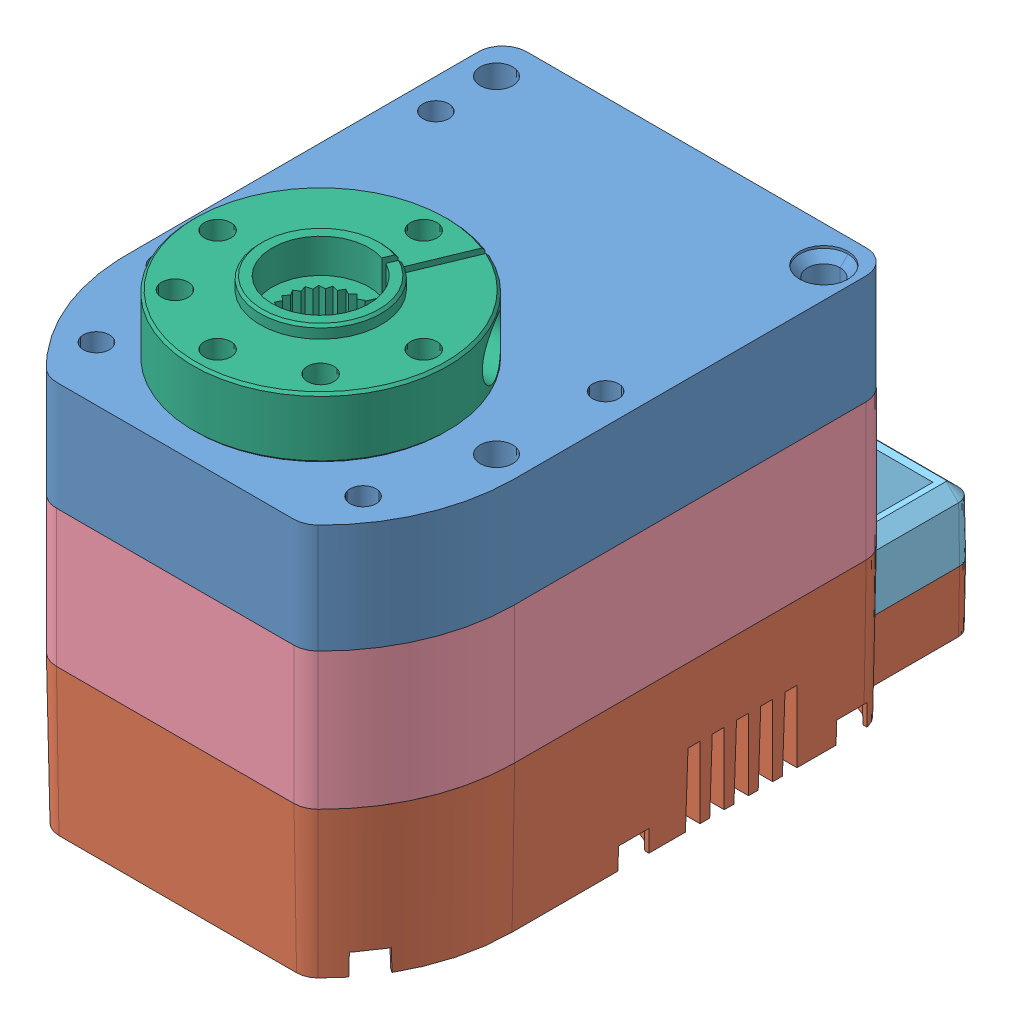
SolidWorks assembly kondo_servo_motor, configuration ﾃﾞﾌｫﾙﾄ. Lengths in mm.
Overall size (36.43 44.5 53.48).
7 component instances, 6 part files, 0 mates.
Components (placement in the parent):
- 60K-アッパーケース-1: 60K-アッパーケース [ﾃﾞﾌｫﾙﾄ] at (0 21.5195 0) x (0.000004 0 1) z (0 1 0) size (47.43 36.43 9)
- 60K-ボトムケースASSY-1: 60K-ボトムケースASSY [ﾃﾞﾌｫﾙﾄ] at (0 -4.4805 0) size (32 18.6 51.5)
  - 60K-ボトムケース-1: 60K-ボトムケース [ﾃﾞﾌｫﾙﾄ] at (0 5.7 0) size (32 18.6 51.5)
  - 60K-インサートナット_L=7mm-1: 60K-インサートナット_L=7mm [ﾃﾞﾌｫﾙﾄ] at (0 -5 0) x (-0.600327 0 -0.799755) z (-0.799755 0 0.600327) size (4.5 7 4.5)
- 60K-ミドルケース-1: 60K-ミドルケース [ﾃﾞﾌｫﾙﾄ] at (-0.0001 21.5195 0) x (0.000001 0 1) z (0 1 0) size (43 32 13.3)
- 60K-コネクターカバー-1: 60K-コネクターカバー [ﾃﾞﾌｫﾙﾄ] at (0 -4.6805 -31) x (-1 0 0) z (0 0 -1) size (28.8 8.2 10)
- 60K-サーボホーン-1: 60K-サーボホーン [ﾃﾞﾌｫﾙﾄ] at (0 22.0195 0) size (21 7.3 21)
